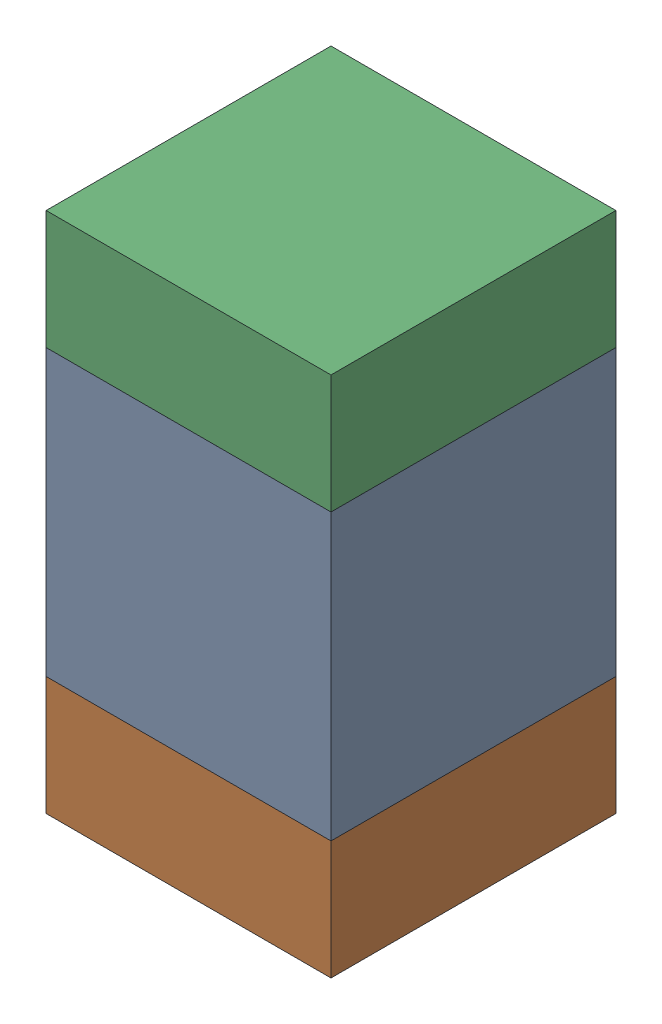
SolidWorks assembly C425PCB, configuration Default. Lengths in mm.
Overall size (0.6 1.1 0.6).
6 component instances, 2 part files, 0 mates.
Components (placement in the parent):
- 761606048-1: 761606048 [Default] at (119.6 113.1 -2.2638) size (0.6 0.6 0.6)
  - Extruded_9-1: Extruded_9 [Default] at origin size (0.6 0.6 0.6)
- 854785296-1: 854785296 [Default] at (119.6 112.675 -2.2638) size (0.6 0.25 0.6)
  - Extruded_10-1: Extruded_10 [Default] at origin size (0.6 0.25 0.6)
- 854785296-2: 854785296 [Default] at (119.6 113.525 -2.2638) size (0.6 0.25 0.6)
  - Extruded_10-1: Extruded_10 [Default] at origin size (0.6 0.25 0.6)
